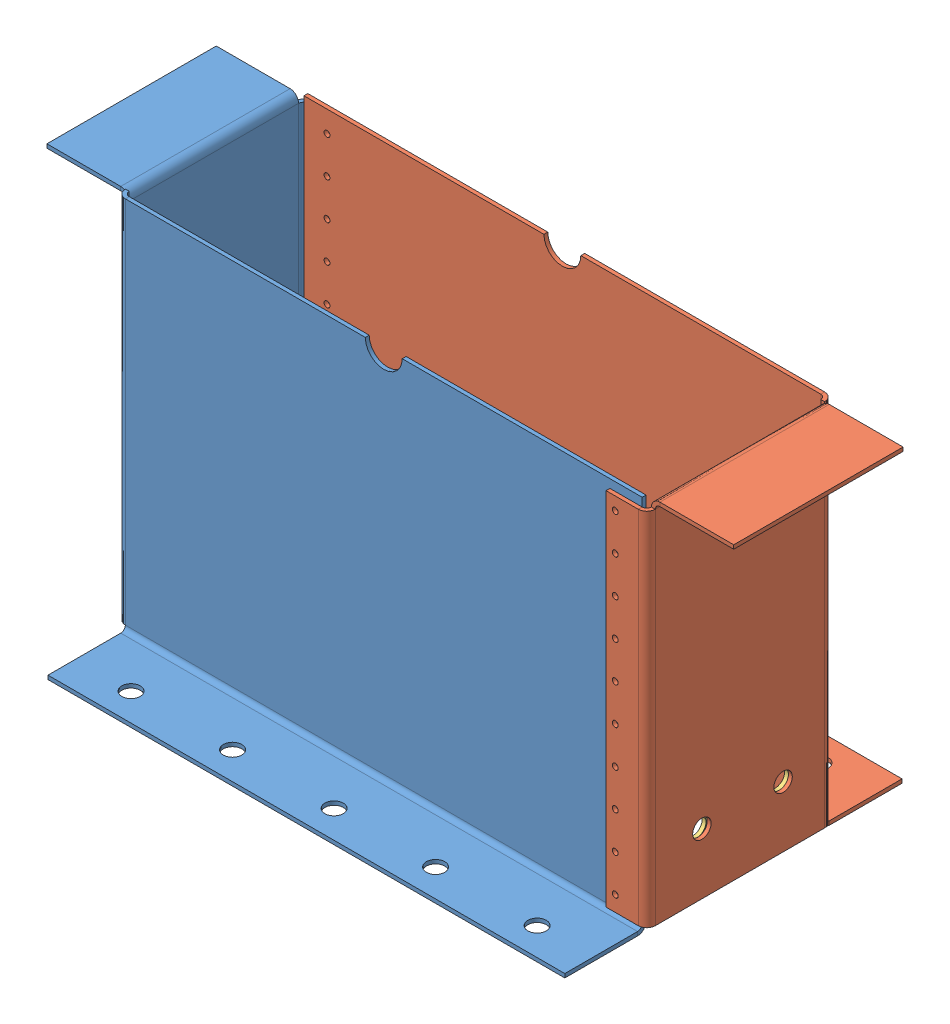
SolidWorks assembly Bottom Assembly Design 6, configuration Default. Lengths in mm.
Overall size (475.21 259.83 232.03).
3 component instances, 3 part files, 8 mates.
Components (placement in the parent):
- Bottom Assembly - Casing Side 1-1: Bottom Assembly - Casing Side 1 [Default] at (-79.4095 295.3728 152.7862) size (415.41 259.83 181.44)
- Bottom Assembly - Casing Side 2-1: Bottom Assembly - Casing Side 2 [Default] at (276.1905 295.3728 27.2568) x (-1 0 0) z (0 0 -1) size (415.41 259.83 181.44)
- Bottom Assembly - Mesh with Screw Holes-1: Bottom Assembly - Mesh with Screw Holes [Default] at (-76.7526 371.5728 150.1293) size (356.12 53.46 120.22)
Mates (geometry in assembly coordinates):
- Parallel1: parallel anti-aligned: plane of Bottom Assembly - Casing Side 1-1 through (98.3905 549.3728 150.1293) normal (0 0 -1); plane of Bottom Assembly - Casing Side 2-1 through (98.3905 549.3728 29.9137) normal (0 0 1)
- Parallel2: parallel anti-aligned: line of Bottom Assembly - Casing Side 1-1 through (85.6905 549.3728 150.1293) axis (-1 0 0); line of Bottom Assembly - Casing Side 2-1 through (-79.4095 549.3728 29.9137) axis (1 0 0)
- Coincident3: coincident anti-aligned: plane of Bottom Assembly - Casing Side 1-1 through (-79.4095 295.3728 27.2568) normal (0 0 1); plane of Bottom Assembly - Casing Side 2-1 through (98.3905 549.3728 27.2568) normal (0 0 -1)
- Coincident4: coincident aligned: line of Bottom Assembly - Casing Side 1-1 through (-79.4095 295.3728 27.2568) axis (0 1 0); line of Bottom Assembly - Casing Side 2-1 through (-79.4095 295.3728 27.2568) axis (0 1 0)
- Coincident5: coincident anti-aligned: line of Bottom Assembly - Casing Side 1-1 through (-57.1845 295.3728 27.2568) axis (-1 0 0); line of Bottom Assembly - Casing Side 2-1 through (-79.4095 295.3728 27.2568) axis (1 0 0)
- Coincident6: coincident anti-aligned: plane of Bottom Assembly - Casing Side 2-1 through (279.3655 295.3728 27.2568) normal (-1 0 0); plane of Bottom Assembly - Mesh with Screw Holes-1 through (279.3655 371.5728 150.1293) normal (1 0 0)
- Coincident7: coincident anti-aligned: line of Bottom Assembly - Casing Side 2-1 through (-79.4095 371.5728 29.9137) axis (1 0 0); line of Bottom Assembly - Mesh with Screw Holes-1 through (273.5337 371.5728 29.9137) axis (-1 0 0)
- Coincident8: coincident anti-aligned: plane of Bottom Assembly - Casing Side 1-1 through (98.3905 549.3728 150.1293) normal (0 0 -1); plane of Bottom Assembly - Mesh with Screw Holes-1 through (-76.7526 368.916 150.1293) normal (0 0 1)
